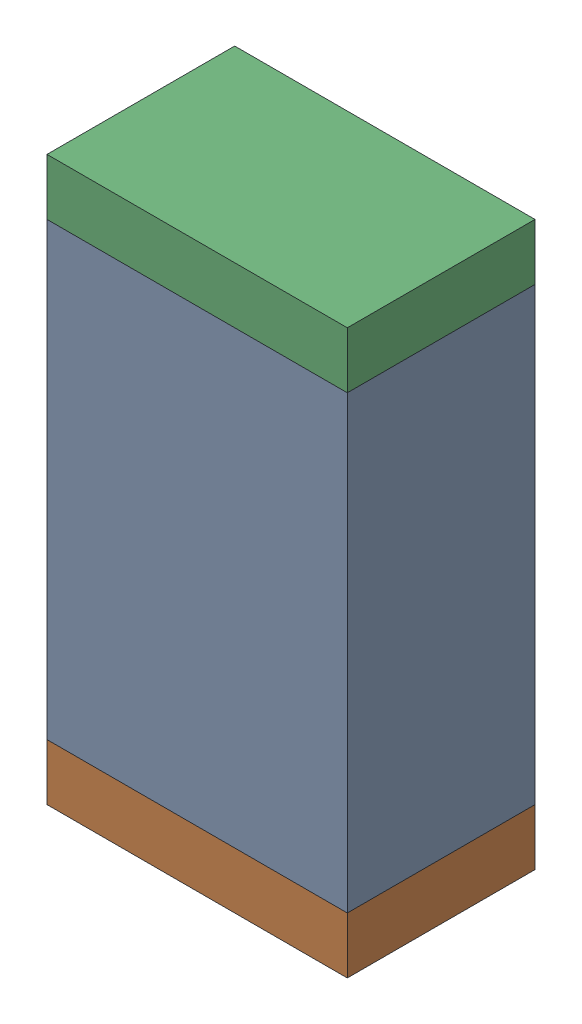
SolidWorks assembly R10, configuration Default. Lengths in mm.
Overall size (0.8 1.5 0.5).
6 component instances, 2 part files, 0 mates.
Components (placement in the parent):
- 810156976-1: 810156976 [Default] at (131.15 36.25 0) size (0.8 1.2 0.5)
  - Extruded_6-1: Extruded_6 [Default] at origin size (0.8 1.2 0.5)
- 810156592-1: 810156592 [Default] at (131.15 35.575 0) size (0.8 0.15 0.5)
  - Extruded_7-1: Extruded_7 [Default] at origin size (0.8 0.15 0.5)
- 810156592-2: 810156592 [Default] at (131.15 36.925 0) size (0.8 0.15 0.5)
  - Extruded_7-1: Extruded_7 [Default] at origin size (0.8 0.15 0.5)
